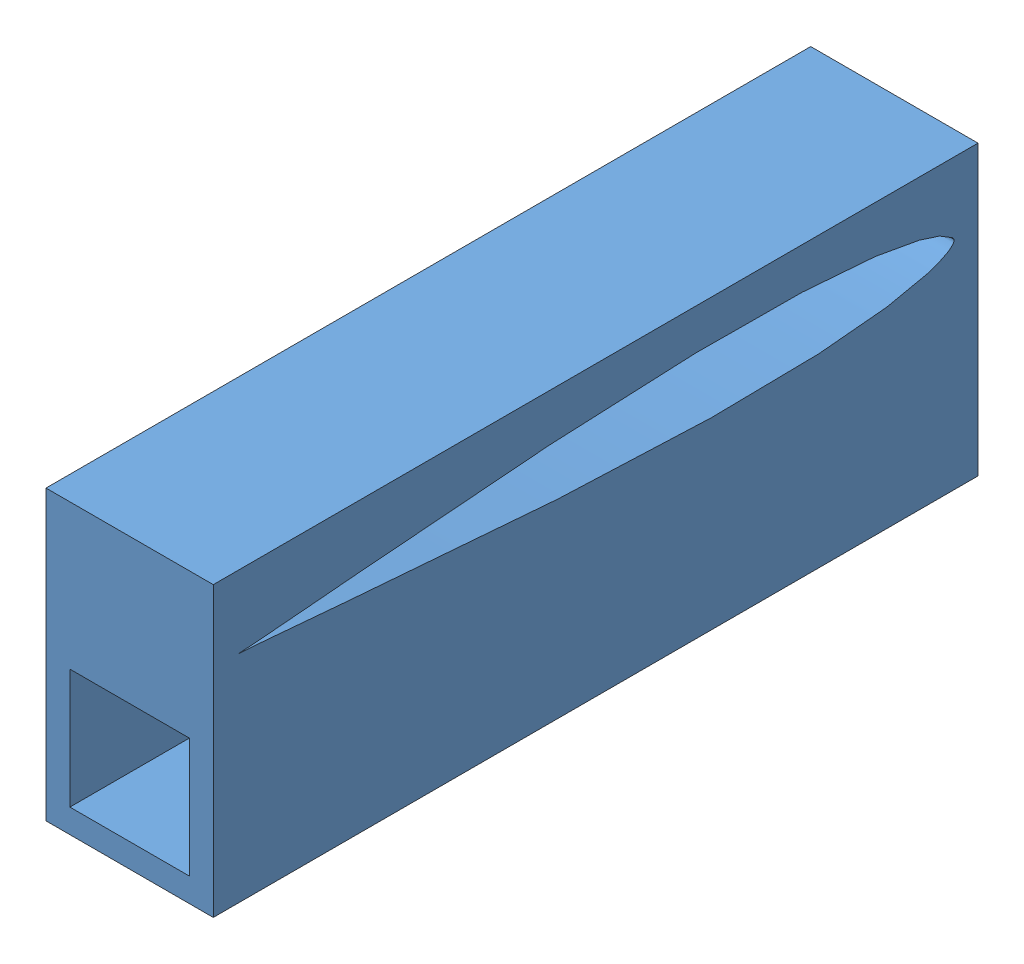
SolidWorks assembly TAIL2023, configuration Default. Lengths in mm.
Overall size (35.5 62.81 203.79).
2 component instances, 2 part files, 0 mates.
Components (placement in the parent):
- bracket^TAIL2023-1: bracket^TAIL2023 [Default] at origin size (35.5 62.81 160) (virtual)
- airfoil 0009-1: airfoil 0009 [Default] at (-28.498 54.9732 -43.7891) x (0 0 1) z (-1 0 0) size (1 0.09 0)
